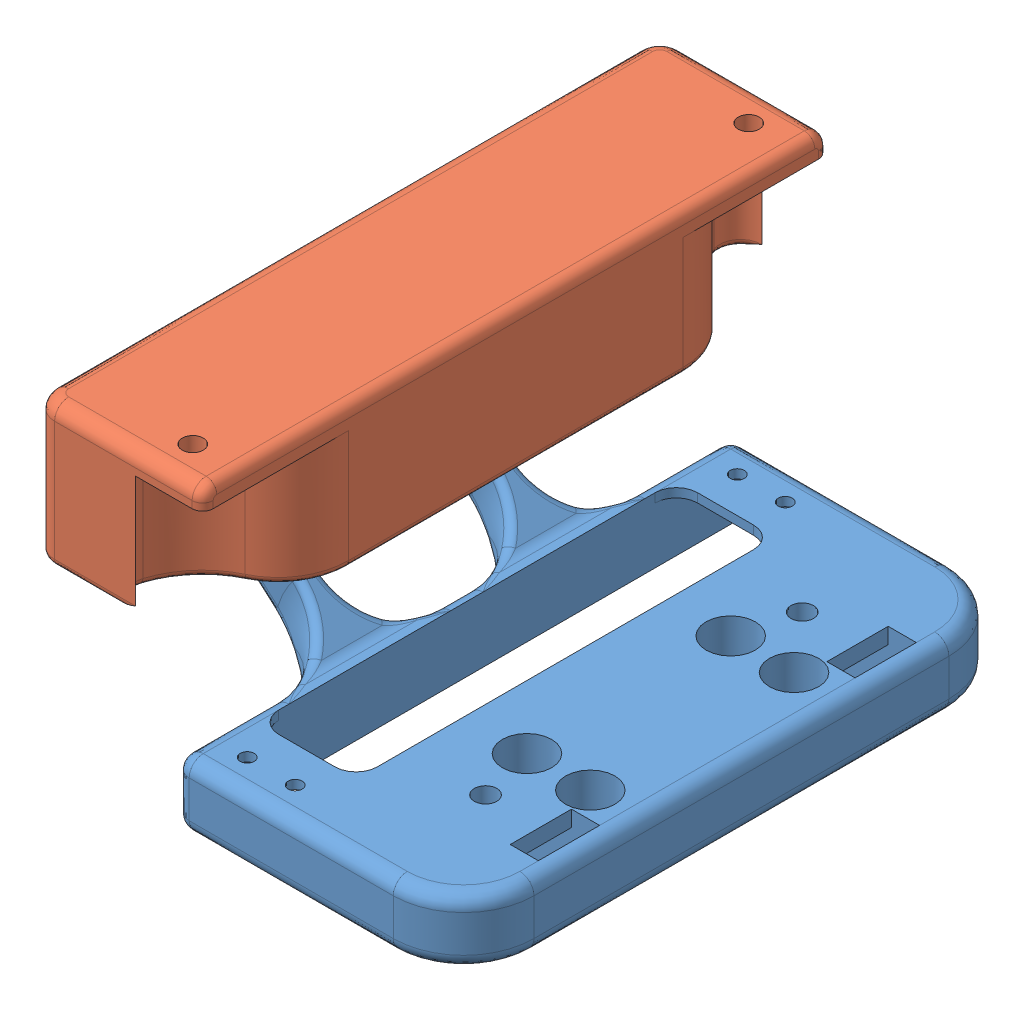
SolidWorks assembly Montagem3, configuration Valor predeterminado. Lengths in mm.
Overall size (66 48.86 89).
2 component instances, 2 part files, 2 mates.
Components (placement in the parent):
- Suporte-Array-Movel-1: Suporte-Array-Movel [Valor predeterminado] at (-27.6262 9.4598 78.95) size (65 25.86 78.95)
- Suporte-Trava-Array-1: Suporte-Trava-Array [Valor predeterminado] at (0.474 32.0324 82.8484) x (0.000123 -1 0) z (0 0 -1) size (30 34.04 89)
Mates (geometry in assembly coordinates):
- Concêntrico2: concentric anti-aligned: circle of Suporte-Array-Movel-1; circle of Suporte-Trava-Array-1
- Distância1: distance = 0.5 mm anti-aligned: plane of Suporte-Trava-Array-1 through (-31.503 32.0284 82.45) normal (0 0 -1); plane of Suporte-Array-Movel-1 through (-27.6262 9.4598 81.95) normal (0 0 1)
